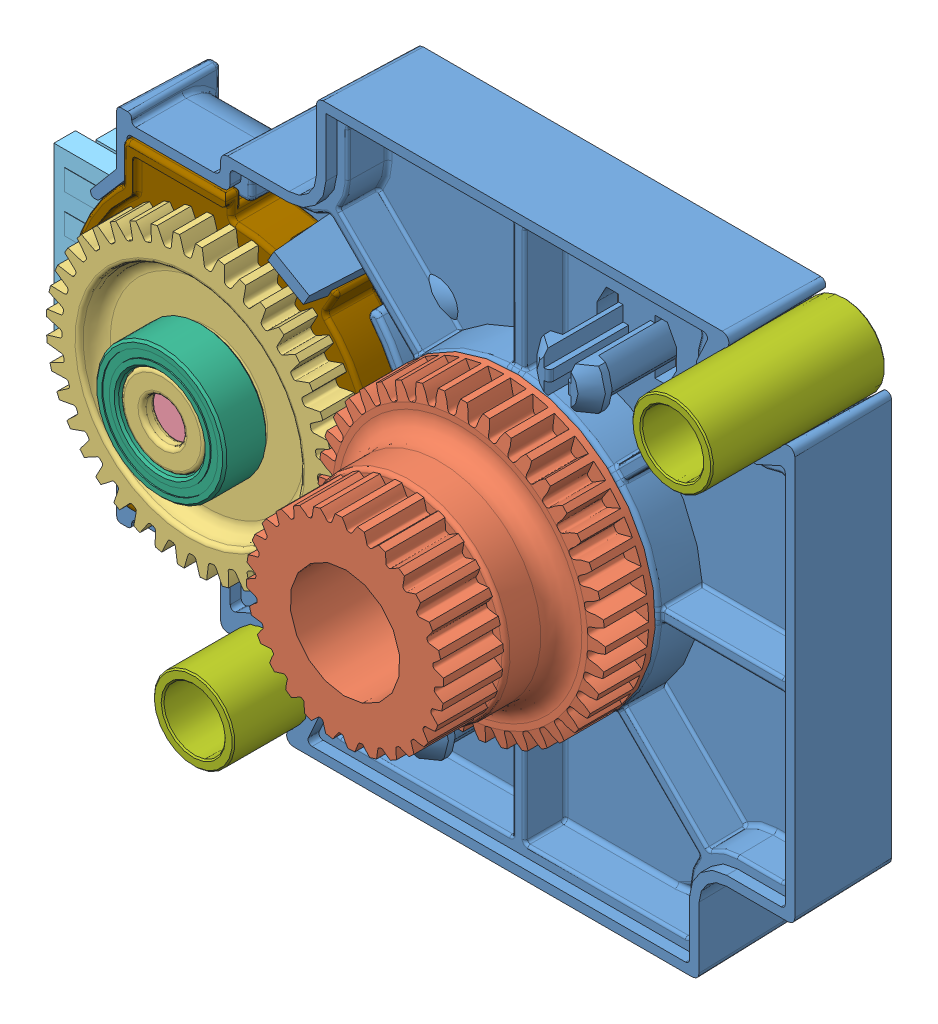
SolidWorks assembly 20-701 Integrated_Encoder, configuration Default. Lengths in mm.
Overall size (58.06 43.13 22.65).
11 component instances, 10 part files, 0 mates.
Components (placement in the parent):
- 217-4783-001 Rev3-1: 217-4783-001 Rev3 [Default] at (0 0 2.75) (suppressed, hidden)
- 217-4783-002 Rev7_Sealed Config-1: 217-4783-002 Rev7_Sealed Config [Default] at (0 0 -7.2) x (0 1 0) z (0 0 1) size (42 51.56 9.32)
- 217-4783-005 Rev7_40t_spur_REF_14deg-1: 217-4783-005 Rev7_40t_spur_REF_14deg [Default] at (0 0 5.95) x (0.660339 0.750968 0) z (0 0 1) size (21.16 21.1 17.1)
- 217-4783-004 Rev2_40t_spur_REF_14deg-1: 217-4783-004 Rev2_40t_spur_REF_14deg [Default] at (-20.05 0 5.2) x (-0.718289 0.695745 0) z (0 0 1) size (21.07 21.07 4.88)
- 217-4783-008 Rev2-1: 217-4783-008 Rev2 [Default] at (-20.05 0 2.2) x (0.307149 -0.951661 0) z (0.951661 0.307149 0) size (5 4 5)
- PCBA Rev3-1: PCBA Rev3 [Default] at (-20.05 0 -2.1252) x (0 1 0) z (-1 0 0) size (15.93 10.15 24.44)
- 217-2788-001 Rev3_57155K375-1: 217-2788-001 Rev3_57155K375 [Default] at (-20.05 0 3.8125) x (-0.99574 0.092202 0) z (0 0 1) size (9.53 9.53 3.17)
- 217-4783-006 Rev3-1: 217-4783-006 Rev3 [Default] at (17.5 17.5 -0.85) x (-0.867641 0.497191 0) z (0 0 1) size (5.9 5.9 12.7)
- 217-4783-006 Rev3-2: 217-4783-006 Rev3 [Default] at (-17.5 -17.5 -0.85) x (0.825154 -0.564908 0) z (0 0 1) size (5.9 5.9 12.7)
- 217-4783-007 Rev1-1: 217-4783-007 Rev1 [Default] at (-16.45 0 -5.2) x (0 1 0) z (0 0 1) size (6 10.71 3.56)
- 217-4783-003 Rev4-1: 217-4783-003 Rev4 [Default] at (-20.05 0 -1.02) x (0 1 0) z (0 0 1) size (23.4 21.71 4.21)
